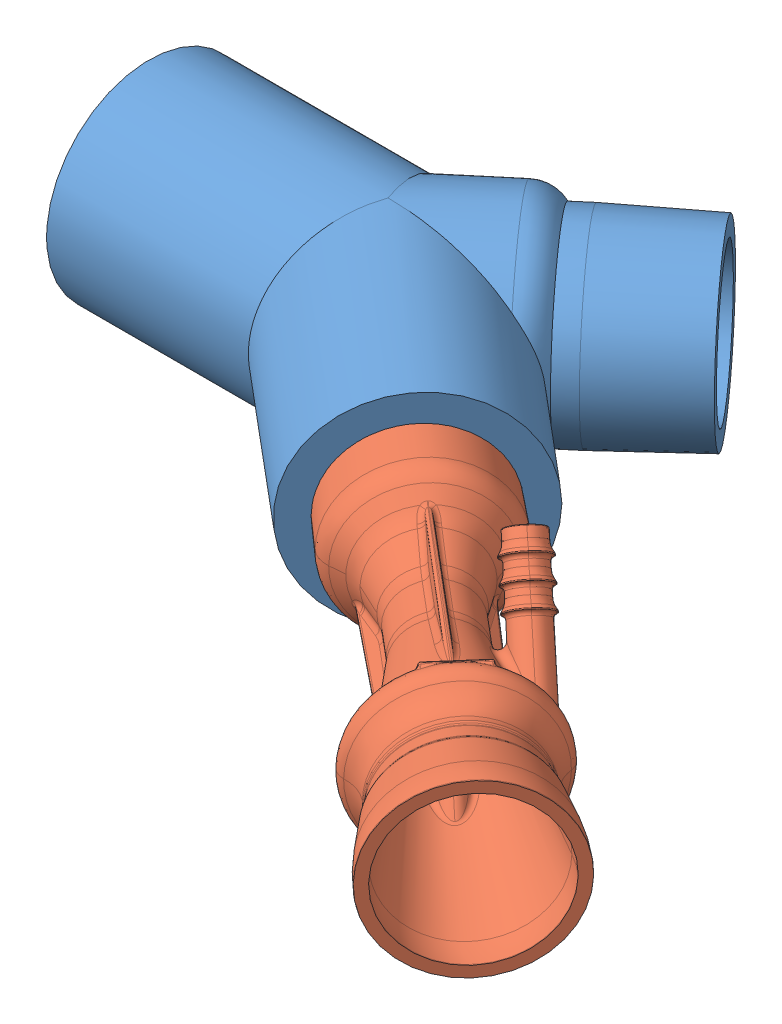
SolidWorks assembly Assem1, configuration Default. Lengths in mm.
Overall size (120.82 30.15 106.94).
2 component instances, 2 part files, 1 mates.
Components (placement in the parent):
- Y_Oxygen_Connector-1: Y_Oxygen_Connector [Default] at (27.3233 40.0222 51.3043) size (71.45 30 66.06)
- Respirator-free reanimation Venturi's valve (rev. 4) FiO2-40 Vertical, 1-piece-1: Respirator-free reanimation Venturi's valve (rev. 4) FiO2-40 Vertical, 1-piece [Default] at (104.9616 40.0222 116.4506) x (0.642712 -0.015378 -0.765954) z (0.766044 0 0.642788) size (25 27.46 76.32)
Mates (geometry in assembly coordinates):
- Concentric1: concentric aligned: cylinder of Y_Oxygen_Connector-1 through (38.0479 40.0222 60.3033) axis (0.766044 0 0.642788) radius 11.075; cone of Respirator-free reanimation Venturi's valve (rev. 4) FiO2-40 Vertical, 1-piece-1 through (46.4992 40.0222 67.3948) axis (0.766044 0 0.642788)
